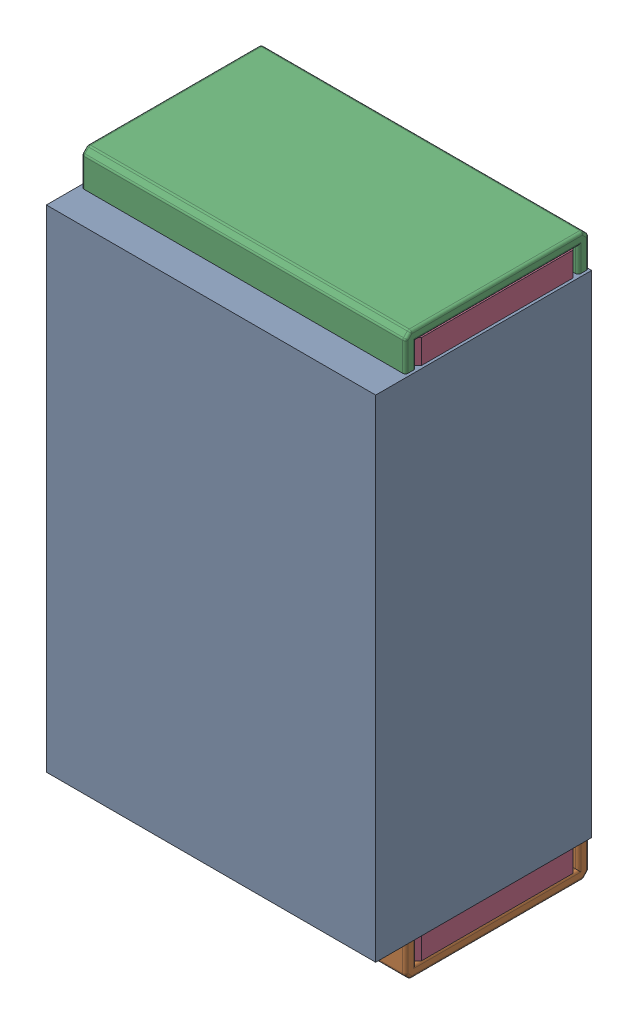
SolidWorks assembly R6, configuration Default. Lengths in mm.
Overall size (0.61 1.04 0.4).
3 component instances, 2 part files, 0 mates.
Components (placement in the parent):
- 1088881848-1: 1088881848 [Default] at (4.925 40.15 0) size (0.61 0.91 0.4)
  - Extruded-1-1: Extruded-1 [Default] at origin size (0.61 0.91 0.4)
- R0402-1: R0402 [Default] at (4.925 40.1499 0) x (0 -1 0) z (-1 0 0) size (1.04 0.34 0.6)
